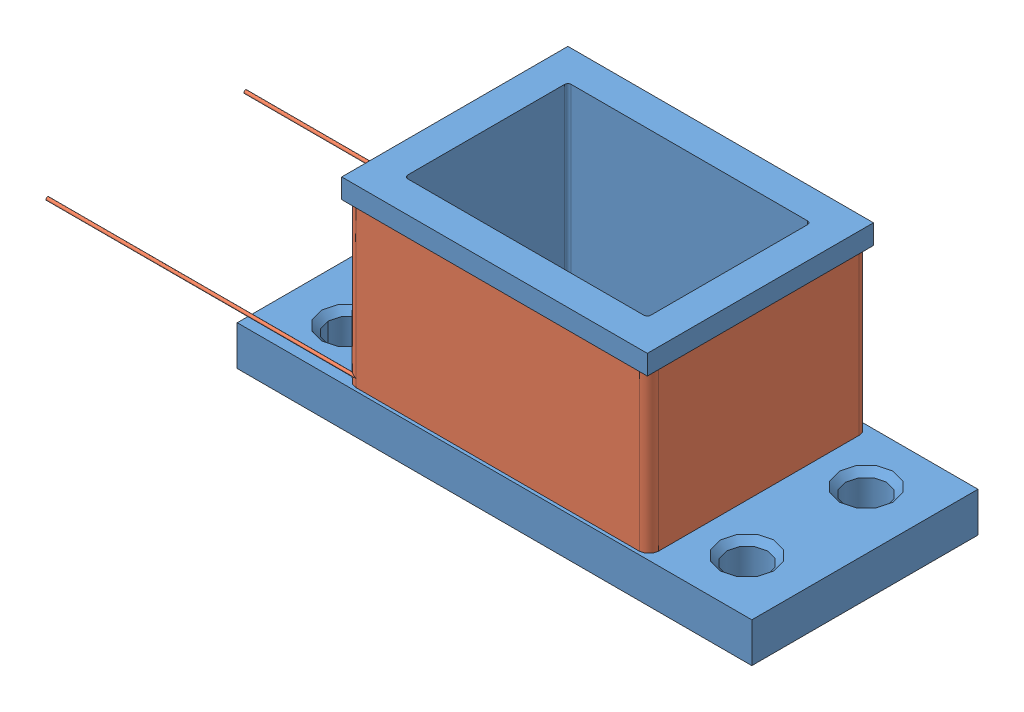
SolidWorks assembly 3510-260-1, configuration Default. Lengths in mm.
Overall size (56.69 17.45 18.08).
2 component instances, 2 part files, 3 mates.
Components (placement in the parent):
- 3510-260 D-1: 3510-260 D [Default] at (-10.6169 -5.4293 1.5492) size (41.15 17.45 18.08)
- 3510-260-1 Coil-1: 3510-260-1 Coil [Default] at (22.0475 -2.2543 1.2952) x (0 0 -1) z (0 1 0) size (17.58 48.21 12.7)
Mates (geometry in assembly coordinates):
- Coincident1: coincident anti-aligned: plane of 3510-260 D-1 through (20.6759 -32.6536 -0.2034) normal (0 0 1); plane of 3510-260-1 Coil-1 through (20.6759 10.4457 -0.2034) normal (0 0 -1)
- Coincident2: coincident anti-aligned: plane of 3510-260 D-1 through (-0.7617 -32.6536 -14.783) normal (-1 0 0); plane of 3510-260-1 Coil-1 through (-0.7617 10.4457 -0.2034) normal (1 0 0)
- Coincident4: coincident anti-aligned: plane of 3510-260 D-1 through (-10.6169 -2.2543 1.5492) normal (0 1 0); plane of 3510-260-1 Coil-1 through (-2.1333 -2.2543 1.2952) normal (0 -1 0)
